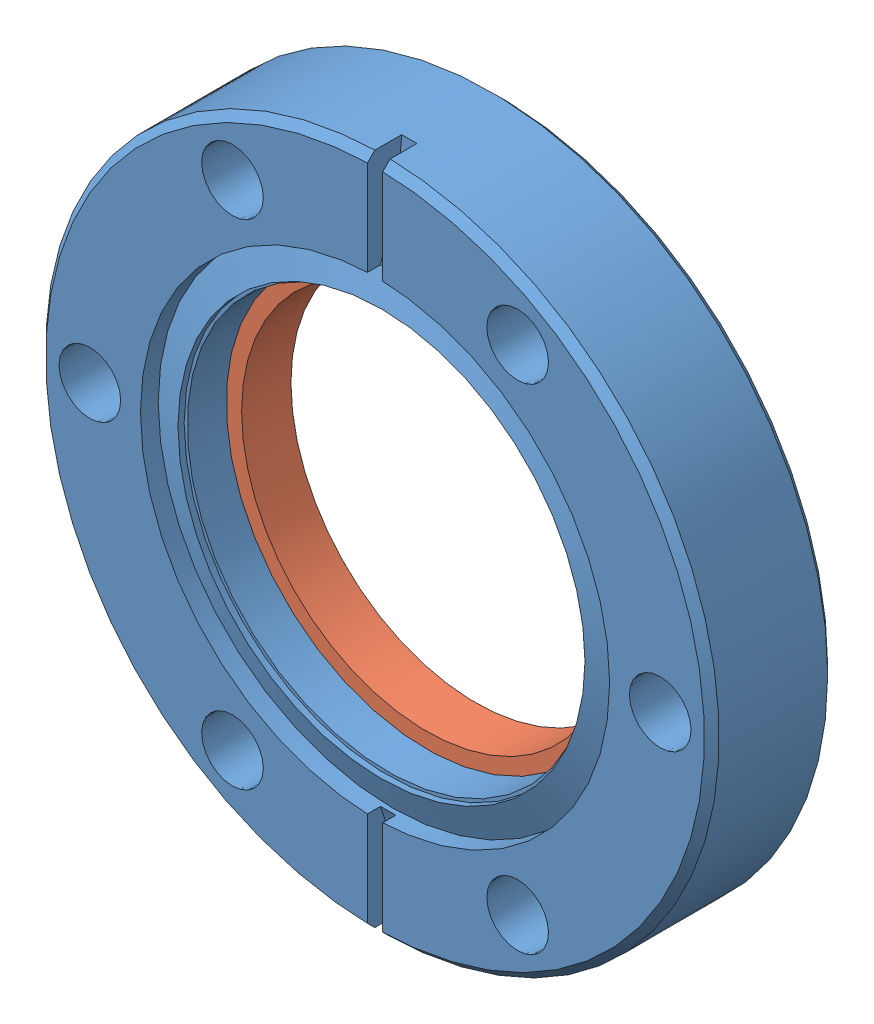
SolidWorks assembly RGAflange, configuration Default. Lengths in mm.
Overall size (69.34 69.34 12.7).
2 component instances, 2 part files, 0 mates.
Components (placement in the parent):
- 130094_1-1: 130094_1 [Default] at (-8.8308 6.0802 -6.35) size (69.34 69.34 12.7)
- glass_1-1: glass_1 [Default] at (-8.8308 6.0802 1.0414) x (-1 0 0) z (0 0 -1) size (44.7 44.7 5.08)
